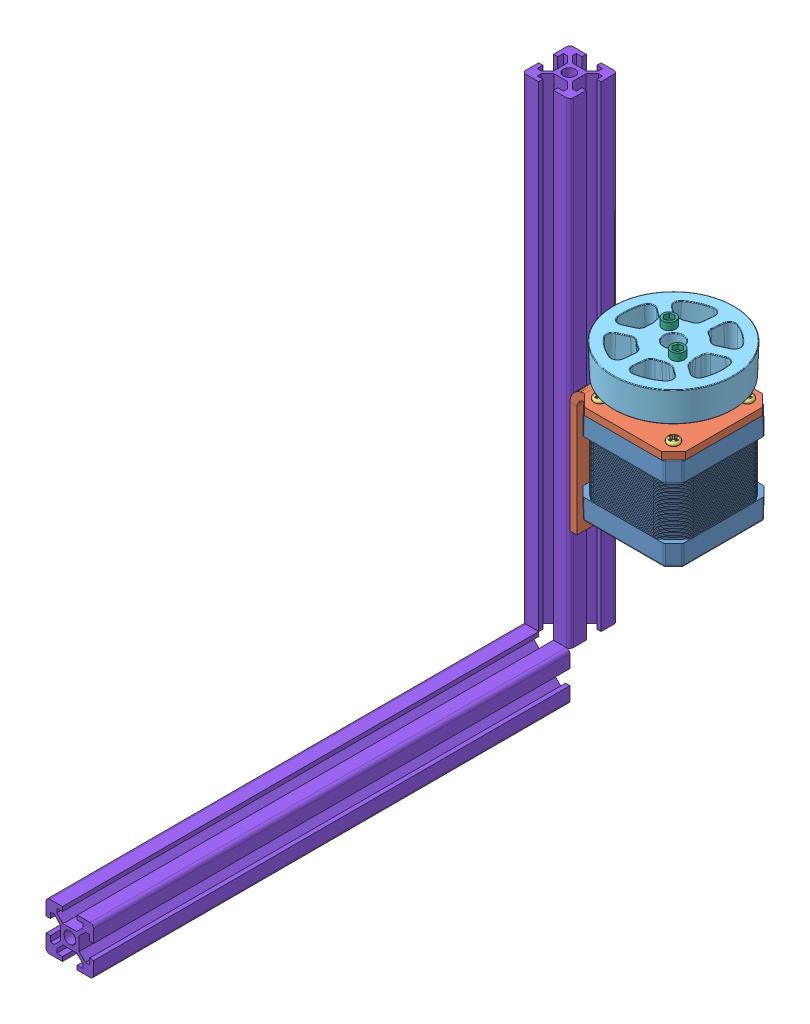
SolidWorks assembly Main Assembly, configuration Default. Lengths in mm.
Overall size (87.28 222.91 251.61).
20 component instances, 9 part files, 43 mates.
Components (placement in the parent):
- Nema 17 Stepper Motor-1: Nema 17 Stepper Motor [Default] at (40.8541 -134.1201 98.738) size (42 55.5 48)
- Stepper Motor Mount 2020E-1: Stepper Motor Mount 2020E [Default] at (12.9267 -104.1201 129.1996) x (0 0 -1) z (0 -1 0) size (42.3 68.51 53.04)
- Screw-1: Screw [Default] at (25.3541 -101.0822 83.238) size (5 33.46 5)
- Screw-2: Screw [Default] at (25.3541 -101.0822 114.238) size (5 33.46 5)
- Screw-3: Screw [Default] at (56.3541 -101.0822 83.238) size (5 33.46 5)
- Screw-4: Screw [Default] at (56.3541 -101.0822 114.238) size (5 33.46 5)
- am-3669 5mm Single Boss Hex Nub with Set Screw REV2-1: am-3669 5mm Single Boss Hex Nub with Set Screw REV2 [Default] at (40.077 -108.3415 107.3876) x (0.987388 0 -0.158321) z (0 1 0) size (16 17 10)
- am-3572 2IN 8mm Compliant Wheel REV2-1: am-3572 2IN 8mm Compliant Wheel REV2 [Default] at (40.8541 -79.3822 98.738) x (-0.586239 0 0.810138) z (0 -1 0) size (50.78 50.78 12.7)
- M3_20D-1: M3_20D [Default] at (34.373 -99.3822 94.048) size (5.5 23 5.5)
- M3_20D-2: M3_20D [Default] at (47.3352 -99.3822 103.4279) size (5.5 23 5.5)
- M4_10D-1: M4_10D [Default] at (3.4913 -141.6201 101.8501) x (0.814295 -0.580451 0) z (0.580451 0.814295 0) size (7 14 7)
- M4_10D-2: M4_10D [Default] at (3.4913 -116.6201 101.8501) x (0.990978 -0.134024 0) z (0.134024 0.990978 0) size (7 14 7)
- M4_10D-3: M4_10D [Default] at (6.5291 -141.6201 104.888) x (0 -1 0) z (0 0 1) size (7 14 7)
- M4_10D-4: M4_10D [Default] at (6.5291 -116.6201 104.888) x (0 -1 0) z (0 0 1) size (7 14 7)
- 2020E-1: 2020E [Default] at (3.4913 2.6584 104.888) x (1 0 0) z (0 -1 0) size (28.93 26.3 200)
- T-Nut M4 20 Series-5: T-Nut M4 20 Series [Default] at (8.1913 -141.6201 104.888) x (0 0 -1) z (0 -1 0) size (10.3 4.96 5.96)
- T-Nut M4 20 Series-6: T-Nut M4 20 Series [Default] at (3.4913 -141.6201 100.188) x (1 0 0) z (0 1 0) size (10.3 4.96 5.96)
- T-Nut M4 20 Series-7: T-Nut M4 20 Series [Default] at (3.4913 -116.6201 100.188) x (1 0 0) z (0 1 0) size (10.3 4.96 5.96)
- T-Nut M4 20 Series-8: T-Nut M4 20 Series [Default] at (8.1913 -116.6201 104.888) x (0 0 -1) z (0 -1 0) size (10.3 4.96 5.96)
- 2020E-2: 2020E [Default] at (3.4913 -207.3416 114.888) size (28.93 26.3 200)
Mates (geometry in assembly coordinates):
- Coincident1: coincident anti-aligned: plane of Nema 17 Stepper Motor-1 through (40.8541 -104.1201 98.738) normal (0 1 0); plane of Stepper Motor Mount 2020E-1 through (12.9267 -104.1201 129.1996) normal (0 -1 0)
- Concentric1: concentric aligned: cylinder of Nema 17 Stepper Motor-1 through (40.8541 -87.6201 98.738) axis (0 -1 0) radius 2.5; cylinder of Stepper Motor Mount 2020E-1 through (40.8541 -101.0822 98.738) axis (0 -1 0) radius 11
- Concentric2: concentric aligned: cylinder of Nema 17 Stepper Motor-1 through (56.3541 -102.1201 83.238) axis (0 -1 0) radius 1.5; cylinder of Stepper Motor Mount 2020E-1 through (56.3541 -101.0822 83.238) axis (0 -1 0) radius 1.5
- Coincident2: coincident anti-aligned: plane of Stepper Motor Mount 2020E-1 through (12.9267 -101.0822 129.1996) normal (0 1 0); plane of Screw-1 through (26.8541 -101.0822 83.238) normal (0 -1 0)
- Concentric4: concentric aligned: cylinder of Stepper Motor Mount 2020E-1 through (25.3541 -101.0822 83.238) axis (0 -1 0) radius 1.5; cylinder of Screw-1 through (25.3541 -132.5822 83.238) axis (0 -1 0) radius 1.5
- Coincident6: coincident anti-aligned: plane of Stepper Motor Mount 2020E-1 through (12.9267 -101.0822 129.1996) normal (0 1 0); plane of Screw-2 through (26.8541 -101.0822 114.238) normal (0 -1 0)
- Concentric5: concentric aligned: cylinder of Stepper Motor Mount 2020E-1 through (25.3541 -101.0822 114.238) axis (0 -1 0) radius 1.5; cylinder of Screw-2 through (25.3541 -132.5822 114.238) axis (0 -1 0) radius 1.5
- Coincident7: coincident anti-aligned: plane of Stepper Motor Mount 2020E-1 through (12.9267 -101.0822 129.1996) normal (0 1 0); plane of Screw-4 through (57.8541 -101.0822 114.238) normal (0 -1 0)
- Concentric6: concentric aligned: cylinder of Stepper Motor Mount 2020E-1 through (56.3541 -101.0822 114.238) axis (0 -1 0) radius 1.5; cylinder of Screw-4 through (56.3541 -132.5822 114.238) axis (0 -1 0) radius 1.5
- Coincident8: coincident anti-aligned: plane of Stepper Motor Mount 2020E-1 through (12.9267 -101.0822 129.1996) normal (0 1 0); plane of Screw-3 through (57.8541 -101.0822 83.238) normal (0 -1 0)
- Concentric7: concentric aligned: cylinder of Stepper Motor Mount 2020E-1 through (56.3541 -101.0822 83.238) axis (0 -1 0) radius 1.5; cylinder of Screw-3 through (56.3541 -132.5822 83.238) axis (0 -1 0) radius 1.5
- Distance1: distance = 2 mm anti-aligned: plane of Stepper Motor Mount 2020E-1 through (12.9267 -101.0822 129.1996) normal (0 1 0); plane of am-3669 5mm Single Boss Hex Nub with Set Screw REV2-1 through (45.6198 -99.0822 90.5186) normal (0 -1 0)
- Concentric8: concentric aligned: circle of Stepper Motor Mount 2020E-1; cylinder of am-3669 5mm Single Boss Hex Nub with Set Screw REV2-1 through (40.8541 -89.0822 98.738) axis (0 -1 0) radius 4
- Parallel2: parallel aligned: plane of Nema 17 Stepper Motor-1 through (42.0186 -101.6201 96.5257) normal (-0.158321 0 -0.987388); plane of am-3669 5mm Single Boss Hex Nub with Set Screw REV2-1 through (33.5182 -73.6822 91.812) normal (-0.158321 0 -0.987388)
- Concentric19: concentric anti-aligned: cylinder of am-3669 5mm Single Boss Hex Nub with Set Screw REV2-1 through (40.8541 -89.0822 98.738) axis (0 -1 0) radius 4; cylinder of am-3572 2IN 8mm Compliant Wheel REV2-1 through (40.8541 -92.0822 98.738) axis (0 1 0) radius 4
- Concentric20: concentric anti-aligned: cylinder of am-3669 5mm Single Boss Hex Nub with Set Screw REV2-1 through (47.3352 -73.6822 103.4279) axis (0 -1 0) radius 1.4859; cylinder of am-3572 2IN 8mm Compliant Wheel REV2-1 through (47.3352 -92.0822 103.4279) axis (0 1 0) radius 1.75
- Coincident19: coincident anti-aligned: plane of am-3669 5mm Single Boss Hex Nub with Set Screw REV2-1 through (31.6885 -92.0822 92.1054) normal (0 1 0); plane of am-3572 2IN 8mm Compliant Wheel REV2-1 through (40.8541 -92.0822 98.738) normal (0 -1 0)
- Concentric21: concentric anti-aligned: cylinder of am-3572 2IN 8mm Compliant Wheel REV2-1 through (34.373 -92.0822 94.048) axis (0 1 0) radius 1.75; cylinder of M3_20D-1 through (34.373 -79.3822 94.048) axis (0 -1 0) radius 1.5
- Coincident20: coincident anti-aligned: plane of am-3572 2IN 8mm Compliant Wheel REV2-1 through (40.8541 -79.3822 98.738) normal (0 1 0); plane of M3_20D-1 through (34.373 -79.3822 94.048) normal (0 -1 0)
- Concentric22: concentric anti-aligned: cylinder of am-3572 2IN 8mm Compliant Wheel REV2-1 through (47.3352 -92.0822 103.4279) axis (0 1 0) radius 1.75; cylinder of M3_20D-2 through (47.3352 -79.3822 103.4279) axis (0 -1 0) radius 1.5
- Coincident21: coincident anti-aligned: plane of am-3572 2IN 8mm Compliant Wheel REV2-1 through (40.8541 -79.3822 98.738) normal (0 1 0); plane of M3_20D-2 through (47.3352 -79.3822 103.4279) normal (0 -1 0)
- Concentric23: concentric anti-aligned: cylinder of Stepper Motor Mount 2020E-1 through (3.4913 -141.6201 101.8501) axis (0 0 -1) radius 2; cylinder of M4_10D-1 through (3.4913 -141.6201 91.8501) axis (0 0 1) radius 2
- Coincident22: coincident anti-aligned: plane of Stepper Motor Mount 2020E-1 through (12.9267 -104.1201 91.8501) normal (0 0 -1); plane of M4_10D-1 through (3.4913 -141.6201 91.8501) normal (0 0 1)
- Concentric24: concentric anti-aligned: cylinder of Stepper Motor Mount 2020E-1 through (3.4913 -116.6201 101.8501) axis (0 0 -1) radius 2; cylinder of M4_10D-2 through (3.4913 -116.6201 91.8501) axis (0 0 1) radius 2
- Coincident23: coincident anti-aligned: plane of Stepper Motor Mount 2020E-1 through (12.9267 -104.1201 91.8501) normal (0 0 -1); plane of M4_10D-2 through (3.4913 -116.6201 91.8501) normal (0 0 1)
- Coincident26: coincident anti-aligned: plane of Stepper Motor Mount 2020E-1 through (16.5291 -104.1201 129.1996) normal (1 0 0); plane of M4_10D-4 through (16.5291 -116.6201 104.888) normal (-1 0 0)
- Coincident27: coincident anti-aligned: plane of Stepper Motor Mount 2020E-1 through (16.5291 -104.1201 129.1996) normal (1 0 0); plane of M4_10D-3 through (16.5291 -141.6201 104.888) normal (-1 0 0)
- Coincident28: coincident anti-aligned: circle of Stepper Motor Mount 2020E-1; cylinder of M4_10D-3 through (16.5291 -141.6201 104.888) axis (-1 0 0) radius 2
- Concentric27: concentric anti-aligned: cylinder of Stepper Motor Mount 2020E-1 through (6.5291 -116.6201 104.888) axis (1 0 0) radius 2; cylinder of M4_10D-4 through (16.5291 -116.6201 104.888) axis (-1 0 0) radius 2
- Coincident35: coincident anti-aligned: plane of Stepper Motor Mount 2020E-1 through (12.9267 -104.1201 94.888) normal (0 0 1); plane of 2020E-1 through (6.5913 -197.3416 94.888) normal (0 0 -1)
- Coincident36: coincident anti-aligned: plane of Stepper Motor Mount 2020E-1 through (13.4913 -104.1201 129.1996) normal (-1 0 0); plane of 2020E-1 through (13.4913 -197.3416 107.988) normal (1 0 0)
- Coincident37: coincident anti-aligned: plane of 2020E-1 through (11.6913 -197.3416 99.388) normal (-1 0 0); plane of T-Nut M4 20 Series-5 through (11.6913 -141.6201 104.888) normal (1 0 0)
- Parallel5: parallel anti-aligned: plane of 2020E-1 through (11.9913 -197.3416 113.388) normal (0 -1 0); plane of T-Nut M4 20 Series-5 through (11.6913 -138.6951 110.038) normal (0 1 0)
- Concentric28: concentric aligned: cylinder of M4_10D-3 through (20.5291 -141.6201 104.888) axis (-1 0 0) radius 3.5; circle of T-Nut M4 20 Series-5
- Coincident38: coincident anti-aligned: plane of 2020E-1 through (11.6913 -197.3416 107.988) normal (-1 0 0); plane of T-Nut M4 20 Series-8 through (11.6913 -116.6201 104.888) normal (1 0 0)
- Parallel6: parallel anti-aligned: plane of 2020E-1 through (11.9913 -197.3416 113.388) normal (0 -1 0); plane of T-Nut M4 20 Series-8 through (11.6913 -113.6951 110.038) normal (0 1 0)
- Concentric29: concentric aligned: unknown of T-Nut M4 20 Series-8; cylinder of M4_10D-4 through (20.5291 -116.6201 104.888) axis (-1 0 0) radius 3.5
- Coincident40: coincident anti-aligned: plane of 2020E-1 through (8.9913 -197.3416 96.688) normal (0 0 1); plane of T-Nut M4 20 Series-7 through (3.4913 -116.6201 96.688) normal (0 0 -1)
- Concentric31: concentric aligned: cylinder of M4_10D-2 through (3.4913 -116.6201 87.8501) axis (0 0 1) radius 3.5; circle of T-Nut M4 20 Series-7
- Coincident41: coincident anti-aligned: plane of 2020E-1 through (8.9913 -197.3416 96.688) normal (0 0 1); plane of T-Nut M4 20 Series-6 through (3.4913 -141.6201 96.688) normal (0 0 -1)
- Concentric32: concentric aligned: cylinder of M4_10D-1 through (3.4913 -141.6201 87.8501) axis (0 0 1) radius 3.5; circle of T-Nut M4 20 Series-6
- Coincident43: coincident: line of 2020E-1 through (11.9913 -197.3416 114.888) axis (-1 0 0); line of 2020E-2 through (11.9913 -197.3416 114.888) axis (-1 0 0)
- Coincident44: coincident: point of 2020E-1; moEndPointRef_w of 2020E-2
